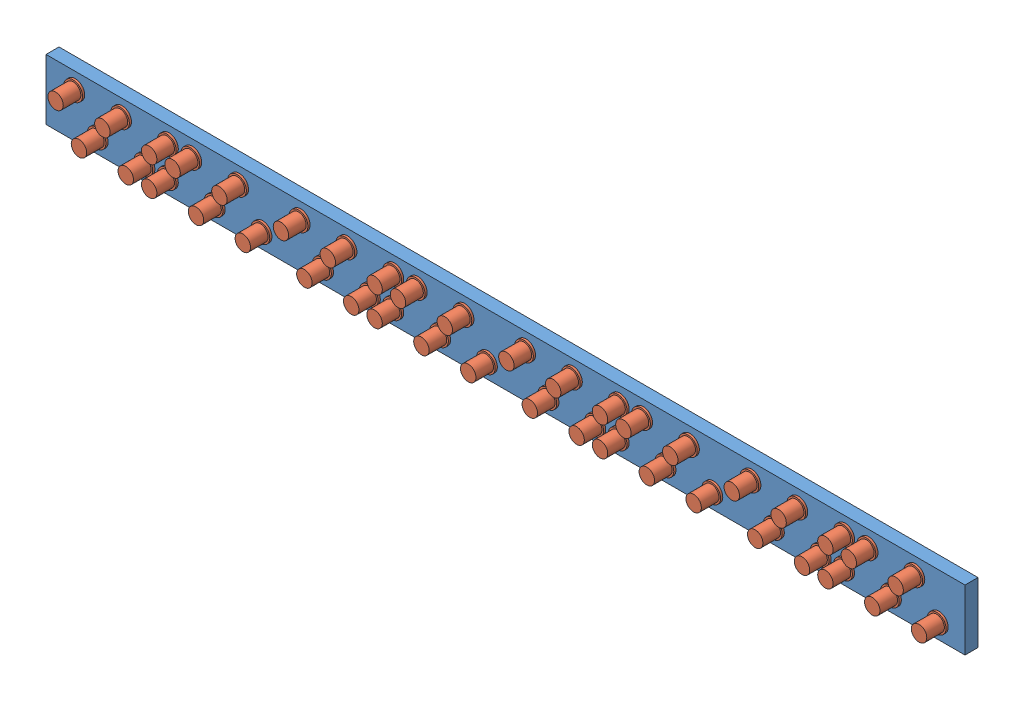
SolidWorks assembly pogo-plate.HV, configuration Default. Lengths in mm.
Overall size (106 7 5.21).
41 component instances, 2 part files, 3 mates.
Components (placement in the parent):
- pogo-plate-1: pogo-plate [Default] at origin size (106 7 1.5)
- pogo-pin.millmax-0926-1-155: pogo-pin.millmax-0926-1 [Default] at (-49.62 1.69 1.75) size (2.16 2.16 5.21)
- pogo-pin.millmax-0926-1-156: pogo-pin.millmax-0926-1 [Default] at (-44.22 1.69 1.75) size (2.16 2.16 5.21)
- pogo-pin.millmax-0926-1-157: pogo-pin.millmax-0926-1 [Default] at (-18.22 1.69 1.75) size (2.16 2.16 5.21)
- pogo-pin.millmax-0926-1-158: pogo-pin.millmax-0926-1 [Default] at (7.78 1.69 1.75) size (2.16 2.16 5.21)
- pogo-pin.millmax-0926-1-159: pogo-pin.millmax-0926-1 [Default] at (33.78 1.69 1.75) size (2.16 2.16 5.21)
- pogo-pin.millmax-0926-1-193: pogo-pin.millmax-0926-1 [Default] at (-23.62 1.69 1.75) size (2.16 2.16 5.21)
- pogo-pin.millmax-0926-1-194: pogo-pin.millmax-0926-1 [Default] at (2.38 1.69 1.75) size (2.16 2.16 5.21)
- pogo-pin.millmax-0926-1-195: pogo-pin.millmax-0926-1 [Default] at (28.38 1.69 1.75) size (2.16 2.16 5.21)
- pogo-pin.millmax-0926-1-161: pogo-pin.millmax-0926-1 [Default] at (-46.92 -1.69 1.75) size (2.16 2.16 5.21)
- pogo-pin.millmax-0926-1-165: pogo-pin.millmax-0926-1 [Default] at (-41.52 -1.69 1.75) size (2.16 2.16 5.21)
- pogo-pin.millmax-0926-1-169: pogo-pin.millmax-0926-1 [Default] at (-38.82 1.69 1.75) size (2.16 2.16 5.21)
- pogo-pin.millmax-0926-1-173: pogo-pin.millmax-0926-1 [Default] at (-38.82 -1.69 1.75) size (2.16 2.16 5.21)
- pogo-pin.millmax-0926-1-162: pogo-pin.millmax-0926-1 [Default] at (-20.92 -1.69 1.75) size (2.16 2.16 5.21)
- pogo-pin.millmax-0926-1-163: pogo-pin.millmax-0926-1 [Default] at (5.08 -1.69 1.75) size (2.16 2.16 5.21)
- pogo-pin.millmax-0926-1-164: pogo-pin.millmax-0926-1 [Default] at (31.08 -1.69 1.75) size (2.16 2.16 5.21)
- pogo-pin.millmax-0926-1-166: pogo-pin.millmax-0926-1 [Default] at (-15.52 -1.69 1.75) size (2.16 2.16 5.21)
- pogo-pin.millmax-0926-1-167: pogo-pin.millmax-0926-1 [Default] at (10.48 -1.69 1.75) size (2.16 2.16 5.21)
- pogo-pin.millmax-0926-1-168: pogo-pin.millmax-0926-1 [Default] at (36.48 -1.69 1.75) size (2.16 2.16 5.21)
- pogo-pin.millmax-0926-1-170: pogo-pin.millmax-0926-1 [Default] at (-12.82 1.69 1.75) size (2.16 2.16 5.21)
- pogo-pin.millmax-0926-1-171: pogo-pin.millmax-0926-1 [Default] at (13.18 1.69 1.75) size (2.16 2.16 5.21)
- pogo-pin.millmax-0926-1-172: pogo-pin.millmax-0926-1 [Default] at (39.18 1.69 1.75) size (2.16 2.16 5.21)
- pogo-pin.millmax-0926-1-174: pogo-pin.millmax-0926-1 [Default] at (-12.82 -1.69 1.75) size (2.16 2.16 5.21)
- pogo-pin.millmax-0926-1-175: pogo-pin.millmax-0926-1 [Default] at (13.18 -1.69 1.75) size (2.16 2.16 5.21)
- pogo-pin.millmax-0926-1-176: pogo-pin.millmax-0926-1 [Default] at (39.18 -1.69 1.75) size (2.16 2.16 5.21)
- pogo-pin.millmax-0926-1-177: pogo-pin.millmax-0926-1 [Default] at (-36.12 1.69 1.75) size (2.16 2.16 5.21)
- pogo-pin.millmax-0926-1-181: pogo-pin.millmax-0926-1 [Default] at (-33.42 -1.69 1.75) size (2.16 2.16 5.21)
- pogo-pin.millmax-0926-1-185: pogo-pin.millmax-0926-1 [Default] at (-30.72 1.69 1.75) size (2.16 2.16 5.21)
- pogo-pin.millmax-0926-1-189: pogo-pin.millmax-0926-1 [Default] at (-28.02 -1.69 1.75) size (2.16 2.16 5.21)
- pogo-pin.millmax-0926-1-178: pogo-pin.millmax-0926-1 [Default] at (-10.12 1.69 1.75) size (2.16 2.16 5.21)
- pogo-pin.millmax-0926-1-179: pogo-pin.millmax-0926-1 [Default] at (15.88 1.69 1.75) size (2.16 2.16 5.21)
- pogo-pin.millmax-0926-1-180: pogo-pin.millmax-0926-1 [Default] at (41.88 1.69 1.75) size (2.16 2.16 5.21)
- pogo-pin.millmax-0926-1-182: pogo-pin.millmax-0926-1 [Default] at (-7.42 -1.69 1.75) size (2.16 2.16 5.21)
- pogo-pin.millmax-0926-1-183: pogo-pin.millmax-0926-1 [Default] at (18.58 -1.69 1.75) size (2.16 2.16 5.21)
- pogo-pin.millmax-0926-1-184: pogo-pin.millmax-0926-1 [Default] at (44.58 -1.69 1.75) size (2.16 2.16 5.21)
- pogo-pin.millmax-0926-1-186: pogo-pin.millmax-0926-1 [Default] at (-4.72 1.69 1.75) size (2.16 2.16 5.21)
- pogo-pin.millmax-0926-1-187: pogo-pin.millmax-0926-1 [Default] at (21.28 1.69 1.75) size (2.16 2.16 5.21)
- pogo-pin.millmax-0926-1-188: pogo-pin.millmax-0926-1 [Default] at (47.28 1.69 1.75) size (2.16 2.16 5.21)
- pogo-pin.millmax-0926-1-190: pogo-pin.millmax-0926-1 [Default] at (-2.02 -1.69 1.75) size (2.16 2.16 5.21)
- pogo-pin.millmax-0926-1-191: pogo-pin.millmax-0926-1 [Default] at (23.98 -1.69 1.75) size (2.16 2.16 5.21)
- pogo-pin.millmax-0926-1-192: pogo-pin.millmax-0926-1 [Default] at (49.98 -1.69 1.75) size (2.16 2.16 5.21)
Mates (geometry in assembly coordinates):
- Coincident1: coincident anti-aligned: plane of pogo-plate-1 through (0 0 1.5) normal (0 0 1); plane of pogo-pin.millmax-0926-1-155 through (-49.62 1.69 1.5) normal (0 0 -1)
- Tangent1: tangent anti-aligned: cylinder of pogo-pin.millmax-0926-1-155 through (-49.62 1.69 3.78) axis (0 0 -1) radius 0.89; plane of assembly through (0 0.8 0) normal (0 1 0)
- Tangent3: tangent aligned: cylinder of pogo-pin.millmax-0926-1-155 through (-49.62 1.69 3.78) axis (0 0 -1) radius 0.89; plane of assembly through (-48.73 0 0) normal (1 0 0)
